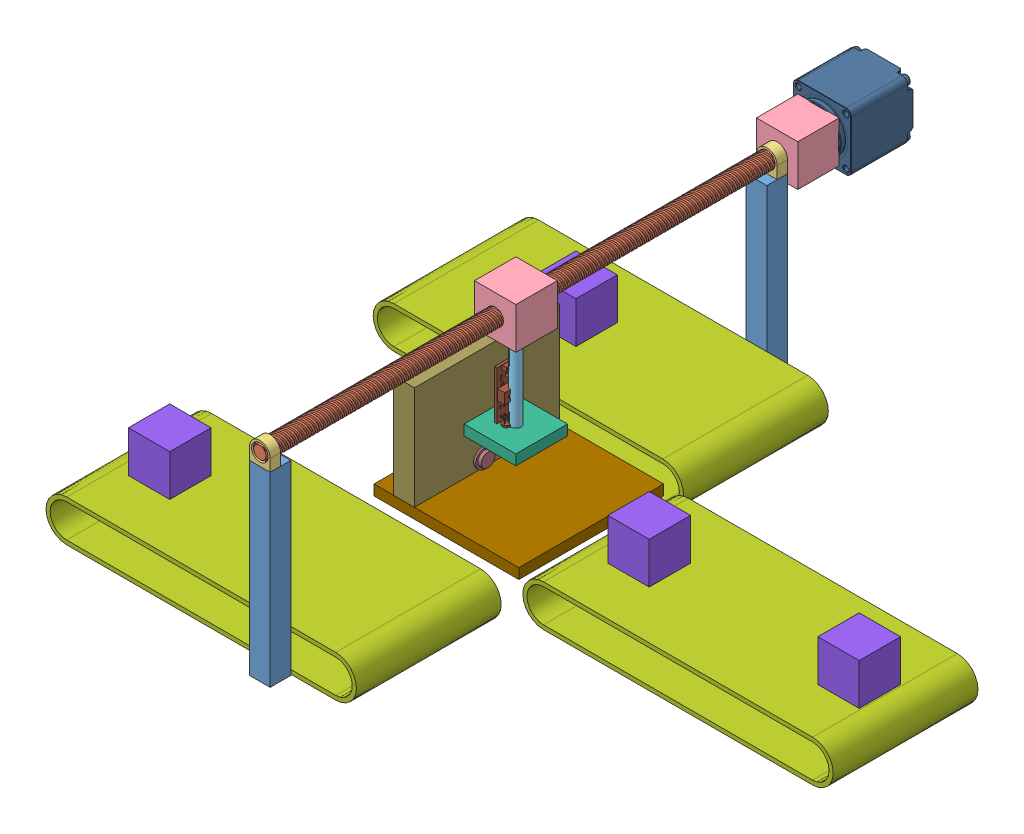
SolidWorks assembly 1, configuration Default. Lengths in mm.
Overall size (302.59 109.86 301.91).
22 component instances, 14 part files, 38 mates.
Components (placement in the parent):
- bar-1: bar [Default] at (-2.9082 -1.6826 93.7624) size (10 90 10)
- Lead Screw 8mm x 250mm.step-1: Lead Screw 8mm x 250mm.step [Default] at (-2.9082 94.177 98.7624) x (-0.981071 0.193649 0) z (0 0 1) size (8 8 250.42)
- bearing-1: bearing [Default] at (-2.9082 94.177 93.7624) x (1 0 0) z (0 -1 0) size (10 5 10.86)
- bearing-4: bearing [Default] at (-2.9082 94.177 -151.2376) x (1 0 0) z (0 -1 0) size (10 5 10.86)
- bar-5: bar [Default] at (-2.9082 -1.6826 -146.2376) size (10 90 10)
- screw slider-1: screw slider [Default] at (-2.9082 94.177 -34.9743) x (0 1 0) z (1 0 0) size (20 20 20)
- slider bar-1: slider bar [Default] at (-2.9082 84.177 -24.9743) x (-0.837169 0 -0.546944) z (0 -1 0) size (5 5 40)
- hanger-1: hanger [Default] at (-2.9082 39.177 -24.9743) x (1 0 0) z (0 1 0) size (25 25 5)
- Belt-1: Belt [Default] at (44.4414 8.8073 -60.9613) x (0 0 1) z (-1 0 0) size (70 20 150)
- Box-2: Box [Default] at (62.1766 18.8073 -24.3264) size (20 20 20)
- plate-1: plate [Default] at (-2.4741 13.8073 -25.9613) size (70 5 70)
- Part11^1-1: Part11^1 [Default] at origin (virtual)
- OUKEDA MOTOR.step-1: OUKEDA MOTOR.step [Default] at (-2.9082 94.177 -202.9376) size (28 30.5 50)
- screw slider-2: screw slider [Default] at (-2.9082 94.177 -171.2376) x (1 0 0) z (0 -1 0) size (20 20 20)
- IR Controller v2.step-1: IR Controller v2.step [Default] at (-7.7449 45.2037 -19.4093) x (0 1 0) z (-0.008727 0 -0.999962) size (34.37 5.36 10.65)
- Belt-3: Belt [Default] at (-106.2515 8.8073 18.7624) x (0 0 1) z (-1 0 0) size (70 20 150)
- Belt-4: Belt [Default] at (21.8537 8.8073 -71.2376) x (0 0 -1) z (1 0 0) size (70 20 150)
- Box-3: Box [Default] at (-90.3503 18.8073 54.8525) size (20 20 20)
- Box-4: Box [Default] at (-56.2039 18.8073 -107.3099) size (20 20 20)
- Box-5: Box [Default] at (163.7051 18.8073 -24.2845) size (20 20 20)
- Part1-1: Part1 [Default] at (-17.9255 43.8073 -25.9613) x (0 1 0) z (-1 0 0) size (50 70 10)
- 22-1: 22 [white_button] at (-25.4255 23.3073 -24.079) x (0 1 0) z (0 0 -1) size (9 10 9)
Mates (geometry in assembly coordinates):
- Coincident3: coincident aligned: line of bar-1 through (-7.9082 88.3174 98.7624) axis (1 0 0); line of bearing-1 through (-7.9082 88.3174 98.7624) axis (1 0 0)
- Coincident4: coincident anti-aligned: plane of bar-1 through (-2.9082 88.3174 93.7624) normal (0 1 0); plane of bearing-1 through (-7.9082 88.3174 98.7624) normal (0 -1 0)
- Coincident5: coincident aligned: line of bar-1 through (2.0918 88.3174 98.7624) axis (0 0 -1); line of bearing-1 through (2.0918 88.3174 98.7624) axis (0 0 -1)
- Coincident15: coincident aligned: plane of bar-1 through (-2.9082 88.3174 93.7624) normal (0 1 0); plane of bar-5 through (-2.9082 88.3174 -146.2376) normal (0 1 0)
- Coincident16: coincident aligned: plane of bar-1 through (2.0918 88.3174 88.7624) normal (1 0 0); plane of bar-5 through (2.0918 88.3174 -151.2376) normal (1 0 0)
- Coincident27: coincident anti-aligned: plane of bearing-4 through (-7.9082 88.3174 -146.2376) normal (0 -1 0); plane of bar-5 through (-2.9082 88.3174 -146.2376) normal (0 1 0)
- Coincident28: coincident anti-aligned: line of bearing-4 through (-7.9082 88.3174 -151.2376) axis (1 0 0); line of bar-5 through (2.0918 88.3174 -151.2376) axis (-1 0 0)
- Coincident29: coincident aligned: line of bearing-4 through (2.0918 88.3174 -146.2376) axis (0 0 -1); line of bar-5 through (2.0918 88.3174 -141.2376) axis (0 0 -1)
- Coincident31: coincident aligned: plane of Lead Screw 8mm x 250mm.step-1 through (-2.9082 94.177 98.7624) normal (0 0 1); circle of bearing-1
- Concentric2: concentric anti-aligned: cylinder of Lead Screw 8mm x 250mm.step-1 through (-2.9082 94.177 -151.2376) axis (0 0 1) radius 4; cylinder of bearing-1 through (-2.9082 94.177 98.7624) axis (0 0 -1) radius 4
- Concentric3: concentric anti-aligned: cylinder of Lead Screw 8mm x 250mm.step-1 through (-2.9082 94.177 -151.2376) axis (0 0 1) radius 4; cylinder of screw slider-1 through (-2.9082 94.177 -14.9743) axis (0 0 -1) radius 4
- Parallel6: parallel anti-aligned: plane of bar-1 through (-7.9082 88.3174 88.7624) normal (0 0 -1); plane of screw slider-1 through (-2.9082 94.177 -14.9743) normal (0 0 1)
- Parallel9: parallel anti-aligned: plane of bar-1 through (2.0918 88.3174 88.7624) normal (1 0 0); plane of screw slider-1 through (-12.9082 84.177 -14.9743) normal (-1 0 0)
- Coincident38: coincident aligned: circle of screw slider-1; circle of slider bar-1
- Coincident39: coincident anti-aligned: circle of slider bar-1; circle of hanger-1
- Parallel10: parallel anti-aligned: plane of bar-5 through (-2.9082 -1.6826 -146.2376) normal (0 -1 0); plane of Belt-1 through (44.4414 18.8073 9.0387) normal (0 1 0)
- Parallel11: parallel anti-aligned: line of bar-5 through (-7.9082 -1.6826 -141.2376) axis (1 0 0); line of Belt-1 through (174.4414 18.8073 -60.9613) axis (-1 0 0)
- Parallel12: parallel aligned: plane of bar-1 through (-2.9082 -1.6826 93.7624) normal (0 -1 0); plane of Belt-1 through (44.4414 -1.1927 9.0387) normal (0 -1 0)
- Coincident47: coincident aligned: plane of Belt-1 through (44.4414 8.8073 9.0387) normal (0 0 1); plane of plate-1 through (-37.4741 18.8073 9.0387) normal (0 0 1)
- Coincident46: coincident aligned: plane of Belt-1 through (44.4414 18.8073 9.0387) normal (0 1 0); plane of plate-1 through (-2.4741 18.8073 -25.9613) normal (0 1 0)
- Coincident62: coincident anti-aligned: plane of Lead Screw 8mm x 250mm.step-1 through (-2.9082 94.177 -151.2376) normal (0 0 -1); circle of screw slider-2
- Coincident63: coincident anti-aligned: circle of OUKEDA MOTOR.step-1; plane of screw slider-2 through (-2.9082 94.177 -171.2376) normal (0 0 -1)
- Coincident64: coincident anti-aligned: plane of bar-5 through (-7.9082 88.3174 -151.2376) normal (0 0 -1); plane of screw slider-2 through (-2.9082 94.177 -151.2376) normal (0 0 1)
- Coincident67: coincident anti-aligned: plane of bar-1 through (-7.9082 88.3174 88.7624) normal (0 0 -1); plane of Belt-3 through (-106.2515 8.8073 88.7624) normal (0 0 1)
- Coincident69: coincident aligned: plane of plate-1 through (-2.4741 18.8073 -25.9613) normal (0 1 0); plane of Belt-3 through (-106.2515 18.8073 88.7624) normal (0 1 0)
- Coincident70: coincident anti-aligned: plane of bar-5 through (-7.9082 88.3174 -141.2376) normal (0 0 1); plane of Belt-4 through (21.8537 8.8073 -141.2376) normal (0 0 -1)
- Coincident71: coincident aligned: plane of plate-1 through (-2.4741 18.8073 -25.9613) normal (0 1 0); plane of Belt-4 through (21.8537 18.8073 -141.2376) normal (0 1 0)
- Coincident72: coincident anti-aligned: plane of bearing-4 through (-2.9082 94.177 -151.2376) normal (0 0 -1); plane of screw slider-2 through (-2.9082 94.177 -151.2376) normal (0 0 1)
- Coincident73: coincident aligned: circle of bearing-4; circle of screw slider-2
- Concentric4: concentric aligned: circle of OUKEDA MOTOR.step-1; circle of screw slider-2
- Coincident75: coincident anti-aligned: plane of Belt-1 through (44.4414 18.8073 9.0387) normal (0 1 0); plane of Box-5 through (163.7051 18.8073 -24.2845) normal (0 -1 0)
- Coincident76: coincident anti-aligned: plane of Belt-4 through (21.8537 18.8073 -141.2376) normal (0 1 0); plane of Box-4 through (-56.2039 18.8073 -107.3099) normal (0 -1 0)
- Coincident77: coincident anti-aligned: plane of Belt-3 through (-106.2515 18.8073 88.7624) normal (0 1 0); plane of Box-3 through (-90.3503 18.8073 54.8525) normal (0 -1 0)
- Coincident78: coincident anti-aligned: plane of Belt-1 through (44.4414 18.8073 9.0387) normal (0 1 0); plane of Box-2 through (62.1766 18.8073 -24.3264) normal (0 -1 0)
- Coincident79: coincident anti-aligned: plane of plate-1 through (-2.4741 18.8073 -25.9613) normal (0 1 0); plane of Part1-1 through (-27.9255 18.8073 -60.9613) normal (0 -1 0)
- Coincident80: coincident anti-aligned: line of plate-1 through (32.5259 18.8073 -60.9613) axis (-1 0 0); line of Part1-1 through (-27.9255 18.8073 -60.9613) axis (1 0 0)
- Coincident81: coincident anti-aligned: plane of Part1-1 through (-17.9255 43.8073 -25.9613) normal (1 0 0); plane of push_button-1 through (-17.9255 27.8073 -24.079) normal (-1 0 0)
- Tangent1: tangent anti-aligned: plane of plate-1 through (-2.4741 18.8073 -25.9613) normal (0 1 0); cylinder of push_button-1 through (-16.9255 23.3073 -24.079) axis (-1 0 0) radius 4.5
